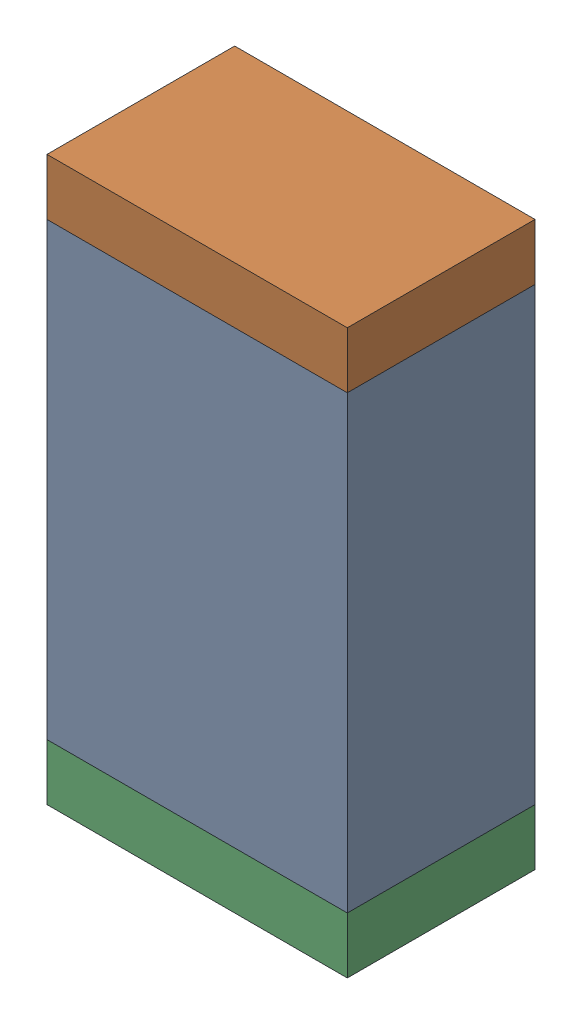
SolidWorks assembly R57, configuration Default. Lengths in mm.
Overall size (0.8 1.5 0.5).
6 component instances, 2 part files, 0 mates.
Components (placement in the parent):
- 810156976-1: 810156976 [Default] at (128.65 67.05 0) size (0.8 1.2 0.5)
  - Extruded_6-1: Extruded_6 [Default] at origin size (0.8 1.2 0.5)
- 810156592-1: 810156592 [Default] at (128.65 67.725 0) size (0.8 0.15 0.5)
  - Extruded_7-1: Extruded_7 [Default] at origin size (0.8 0.15 0.5)
- 810156592-2: 810156592 [Default] at (128.65 66.375 0) size (0.8 0.15 0.5)
  - Extruded_7-1: Extruded_7 [Default] at origin size (0.8 0.15 0.5)
